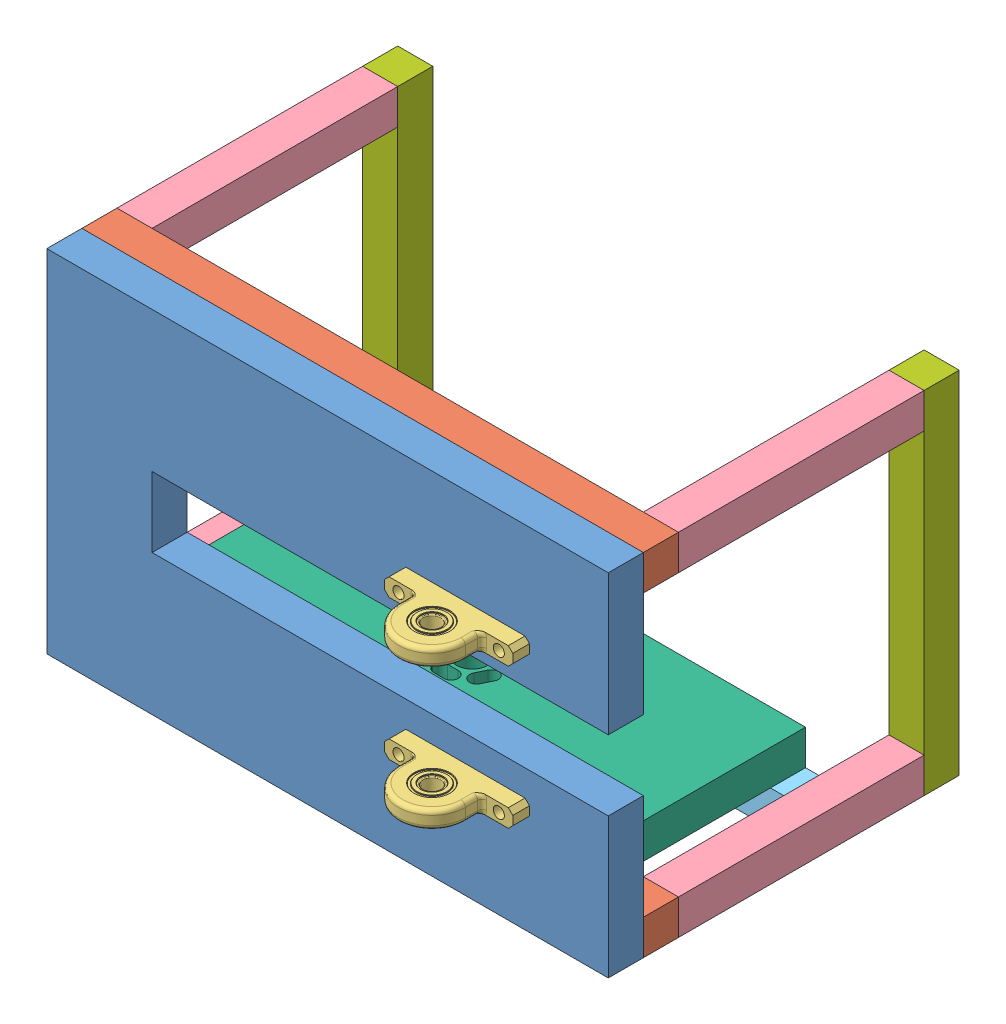
SolidWorks assembly FullAssembly, configuration Default. Lengths in mm.
Overall size (160 100 119.05).
13 component instances, 7 part files, 33 mates.
Components (placement in the parent):
- Top Plate-1: Top Plate [Default] at (12.6277 -7.7073 -30.5038) size (160 100 10)
- Leg160mm-1: Leg160mm [Default] at (119.0901 -63.0591 25.2666) x (0 0 1) z (-1 0 0) size (10 10 160)
- Leg160mm-5: Leg160mm [Default] at (119.0901 26.9409 25.2666) x (0 0 1) z (-1 0 0) size (10 10 160)
- bearing-1: bearing [8600N11] at (78.3776 27.1777 -10.9788) x (1 0 0) z (0 -1 0) size (36.51 19.05 5.08)
- bearing-2: bearing [8600N11] at (78.3776 -12.8223 -10.9788) x (1 0 0) z (0 -1 0) size (36.51 19.05 5.08)
- Leg70mm-1: Leg70mm [Default] at (8.7076 38.9846 -110.5038) size (10 10 70)
- Leg70mm-2: Leg70mm [Default] at (8.7076 -51.0154 -110.5038) size (10 10 70)
- Leg70mm-3: Leg70mm [Default] at (158.7076 -51.0154 -110.5038) size (10 10 70)
- Leg70mm-4: Leg70mm [Default] at (158.7076 38.9846 -110.5038) size (10 10 70)
- Leg140mm-1: Leg140mm [Default] at (-30.9099 -66.9837 -184.9995) x (0 0 -1) z (1 0 0) size (10 10 140)
- generator_side-1: generator_side [Default] at (44.1052 -32.8223 -88.4013) x (0 1 0) z (1 0 0) size (10 60 130)
- Leg100mm-1: Leg100mm [Default] at (156.3976 57.1777 -138.4546) x (1 0 0) z (0 -1 0) size (10 10 100)
- Leg100mm-2: Leg100mm [Default] at (6.3976 -42.8223 -92.5529) x (1 0 0) z (0 1 0) size (10 10 100)
Mates (geometry in assembly coordinates):
- Coincident2: coincident anti-aligned: plane of Top Plate-1 through (12.6277 -7.7073 -30.5038) normal (0 0 -1); plane of Leg160mm-5 through (-40.9099 57.1777 -30.5038) normal (0 0 1)
- Coincident3: coincident aligned: plane of Top Plate-1 through (-40.9099 57.1777 -20.5038) normal (0 1 0); plane of Leg160mm-5 through (-40.9099 57.1777 -40.5038) normal (0 1 0)
- Coincident4: coincident aligned: plane of Top Plate-1 through (119.0901 57.1777 -20.5038) normal (1 0 0); plane of Leg160mm-5 through (119.0901 26.9409 25.2666) normal (1 0 0)
- Coincident5: coincident anti-aligned: plane of Top Plate-1 through (12.6277 -7.7073 -30.5038) normal (0 0 -1); plane of Leg160mm-1 through (-40.9099 -32.8223 -30.5038) normal (0 0 1)
- Coincident7: coincident aligned: plane of Top Plate-1 through (-40.9099 -42.8223 -20.5038) normal (0 -1 0); plane of Leg160mm-1 through (-40.9099 -42.8223 -40.5038) normal (0 -1 0)
- Coincident8: coincident aligned: plane of Top Plate-1 through (119.0901 -42.8223 -20.5038) normal (1 0 0); plane of Leg160mm-1 through (119.0901 -63.0591 25.2666) normal (1 0 0)
- Concentric1: concentric aligned: circle of Top Plate-1; circle of bearing-1
- Coincident11: coincident anti-aligned: plane of Top Plate-1 through (12.6277 -7.7073 -20.5038) normal (0 0 1); plane of bearing-1 through (96.6339 24.6377 -20.5038) normal (0 0 -1)
- Coincident12: coincident anti-aligned: plane of Top Plate-1 through (12.6277 -7.7073 -20.5038) normal (0 0 1); plane of bearing-2 through (96.6339 -15.3623 -20.5038) normal (0 0 -1)
- Concentric2: concentric aligned: circle of Top Plate-1; circle of bearing-2
- Coincident14: coincident anti-aligned: plane of Leg160mm-5 through (-40.9099 57.1777 -40.5038) normal (0 0 -1); plane of Leg70mm-1 through (8.7076 38.9846 -40.5038) normal (0 0 1)
- Coincident15: coincident aligned: plane of Leg160mm-5 through (-40.9099 57.1777 -40.5038) normal (0 1 0); plane of Leg70mm-1 through (-40.9099 57.1777 -40.5038) normal (0 1 0)
- Coincident16: coincident aligned: plane of Leg160mm-5 through (-40.9099 26.9409 25.2666) normal (-1 0 0); plane of Leg70mm-1 through (-40.9099 57.1777 -40.5038) normal (-1 0 0)
- Coincident17: coincident anti-aligned: plane of Leg160mm-1 through (-40.9099 -32.8223 -40.5038) normal (0 0 -1); plane of Leg70mm-2 through (8.7076 -51.0154 -40.5038) normal (0 0 1)
- Coincident18: coincident aligned: plane of Leg160mm-1 through (-40.9099 -42.8223 -40.5038) normal (0 -1 0); plane of Leg70mm-2 through (-40.9099 -42.8223 -40.5038) normal (0 -1 0)
- Coincident19: coincident aligned: plane of Leg160mm-1 through (-40.9099 -63.0591 25.2666) normal (-1 0 0); plane of Leg70mm-2 through (-40.9099 -32.8223 -40.5038) normal (-1 0 0)
- Coincident20: coincident anti-aligned: plane of Leg160mm-1 through (-40.9099 -32.8223 -40.5038) normal (0 0 -1); plane of Leg70mm-3 through (158.7076 -51.0154 -40.5038) normal (0 0 1)
- Coincident21: coincident aligned: plane of Leg160mm-1 through (119.0901 -63.0591 25.2666) normal (1 0 0); plane of Leg70mm-3 through (119.0901 -32.8223 -40.5038) normal (1 0 0)
- Coincident23: coincident aligned: plane of Leg160mm-1 through (-40.9099 -42.8223 -40.5038) normal (0 -1 0); plane of Leg70mm-3 through (109.0901 -42.8223 -40.5038) normal (0 -1 0)
- Coincident24: coincident anti-aligned: plane of Leg160mm-5 through (-40.9099 57.1777 -40.5038) normal (0 0 -1); plane of Leg70mm-4 through (158.7076 38.9846 -40.5038) normal (0 0 1)
- Coincident25: coincident aligned: plane of Leg160mm-5 through (119.0901 26.9409 25.2666) normal (1 0 0); plane of Leg70mm-4 through (119.0901 57.1777 -40.5038) normal (1 0 0)
- Coincident26: coincident aligned: plane of Leg160mm-5 through (-40.9099 57.1777 -40.5038) normal (0 1 0); plane of Leg70mm-4 through (109.0901 57.1777 -40.5038) normal (0 1 0)
- Coincident27: coincident anti-aligned: plane of Leg70mm-3 through (109.0901 -32.8223 -40.5038) normal (-1 0 0); plane of Leg140mm-1 through (109.0901 -66.9837 -184.9995) normal (1 0 0)
- Coincident28: coincident aligned: plane of Leg70mm-2 through (-40.9099 -42.8223 -40.5038) normal (0 -1 0); plane of Leg140mm-1 through (109.0901 -42.8223 -80.5038) normal (0 -1 0)
- Distance1: distance = 60 mm: line of Leg140mm-1 through (109.0901 -42.8223 -90.5038) axis (-1 0 0); line of Top Plate-1 through (-40.9099 -42.8223 -30.5038) axis (1 0 0)
- Coincident34: coincident anti-aligned: plane of Leg160mm-1 through (-40.9099 -32.8223 -40.5038) normal (0 1 0); plane of generator_side-1 through (44.1052 -32.8223 -88.4013) normal (0 -1 0)
- Coincident35: coincident anti-aligned: plane of Top Plate-1 through (12.6277 -7.7073 -30.5038) normal (0 0 -1); plane of generator_side-1 through (105.292 -22.8223 -30.5038) normal (0 0 1)
- Coincident36: coincident anti-aligned: plane of Leg70mm-3 through (158.7076 -51.0154 -110.5038) normal (0 0 -1); plane of Leg100mm-1 through (114.0319 -42.8223 -110.5038) normal (0 0 1)
- Coincident37: coincident aligned: plane of Leg70mm-4 through (109.0901 57.1777 -40.5038) normal (0 1 0); plane of Leg100mm-1 through (161.3394 57.1777 -138.4546) normal (0 1 0)
- Coincident38: coincident aligned: plane of Leg70mm-3 through (119.0901 -32.8223 -40.5038) normal (1 0 0); plane of Leg100mm-1 through (119.0901 -42.8223 -110.5038) normal (1 0 0)
- Coincident39: coincident: plane of Leg70mm-1 through (8.7076 38.9846 -110.5038) normal (0 0 -1); plane of Leg100mm-2 through (-40.9099 57.1777 -110.5038) normal (0 0 1)
- Coincident40: coincident: plane of Leg70mm-1 through (-40.9099 57.1777 -40.5038) normal (0 1 0); plane of Leg100mm-2 through (6.3976 57.1777 -92.5529) normal (0 1 0)
- Coincident41: coincident aligned: plane of Leg70mm-1 through (-40.9099 57.1777 -40.5038) normal (-1 0 0); plane of Leg100mm-2 through (-40.9099 57.1777 -120.5038) normal (-1 0 0)
